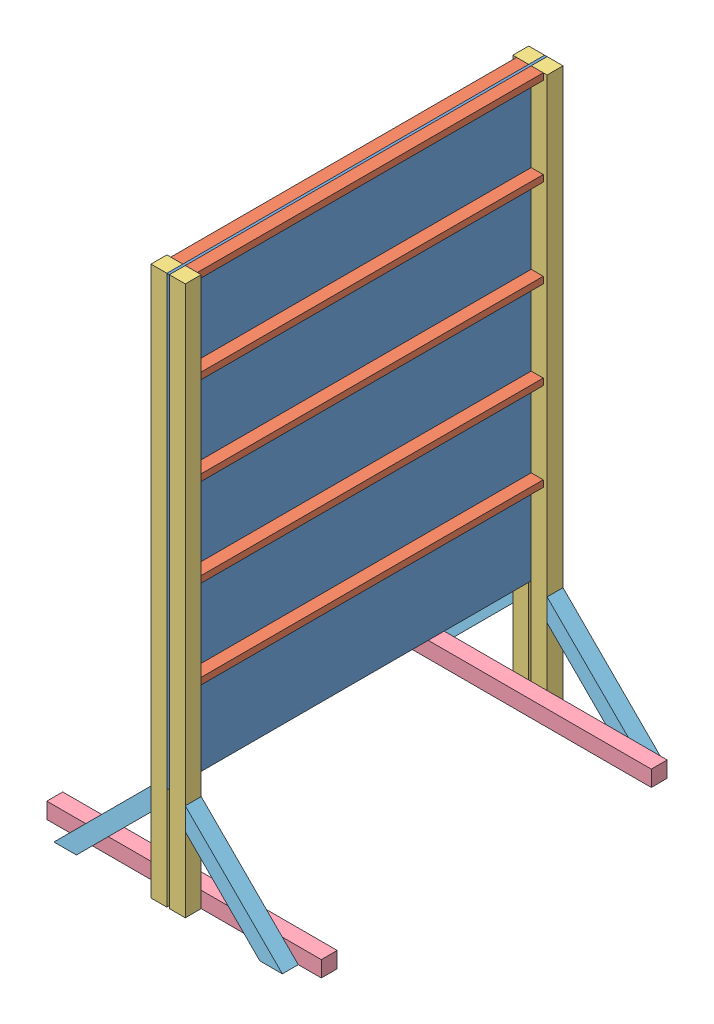
SolidWorks assembly Brett, configuration Standard. Lengths in mm.
Overall size (1000 2041.01 1376).
21 component instances, 5 part files, 60 mates.
Components (placement in the parent):
- Wand-1: Wand [Standard] at (-36.2731 -1608.7946 4318) x (0 0 -1) z (1 0 0) size (1376 1625 9)
- latte1-1: latte1 [Standard] at (-27.2731 -7.7946 3000) size (44 24 1260)
- latte2-1: latte2 [Standard] at (-27.2731 16.2054 2942) x (1 0 0) z (0 -1 0) size (58 58 2000)
- latte2-2: latte2 [Standard] at (-27.2731 16.2054 4260) x (1 0 0) z (0 -1 0) size (58 58 2000)
- latte1-2: latte1 [Standard] at (-27.2731 -649.7946 3000) size (44 24 1260)
- latte1-3: latte1 [Standard] at (-27.2731 -970.7946 3000) size (44 24 1260)
- latte1-4: latte1 [Standard] at (-27.2731 -1291.7946 3000) size (44 24 1260)
- latte1-5: latte1 [Standard] at (-27.2731 -328.7946 3000) size (44 24 1260)
- latte2-3: latte2 [Standard] at (-94.2731 -1983.7946 3000) x (1 0 0) z (0 1 0) size (58 58 2000)
- latte2-4: latte2 [Standard] at (-94.2731 -1983.7946 4318) x (1 0 0) z (0 1 0) size (58 58 2000)
- latte1-6: latte1 [Standard] at (-80.2731 -7.7946 3000) size (44 24 1260)
- latte1-7: latte1 [Standard] at (-80.2731 -328.7946 3000) size (44 24 1260)
- latte1-8: latte1 [Standard] at (-80.2731 -649.7946 3000) size (44 24 1260)
- latte1-9: latte1 [Standard] at (-80.2731 -970.7946 3000) size (44 24 1260)
- latte1-10: latte1 [Standard] at (-80.2731 -1291.7946 3000) size (44 24 1260)
- latte3-1: latte3 [Standard] at (468.2269 -1983.7946 4202) x (0 0 1) z (-1 0 0) size (58 58 1000)
- latte3-2: latte3 [Standard] at (-531.7731 -1983.7946 3058) x (0 0 -1) z (1 0 0) size (58 58 1000)
- latte4-1: latte4 [Standard] at (-10.2853 -1671.2534 3000) x (0 0 -1) z (0.707107 -0.707107 0) size (58 58 500)
- latte4-2: latte4 [Standard] at (-406.8143 -2024.8068 3000) x (0 0 -1) z (0.707107 0.707107 0) size (58 58 500)
- latte4-3: latte4 [Standard] at (343.2681 -2024.8068 4260) x (0 0 1) z (-0.707107 0.707107 0) size (58 58 500)
- latte4-4: latte4 [Standard] at (-53.2609 -1671.2534 4260) x (0 0 1) z (-0.707107 -0.707107 0) size (58 58 500)
Mates (geometry in assembly coordinates):
- Deckungsgleich1: coincident anti-aligned: plane of latte1-1 through (-27.2731 -7.7946 4260) normal (-1 0 0); plane of Wand-1 through (-27.2731 -1608.7946 4318) normal (1 0 0)
- Abstand1: distance = 58 mm aligned: plane of latte1-1 through (-27.2731 -7.7946 3000) normal (0 0 -1); plane of Wand-1 through (-27.2731 -1608.7946 2942) normal (0 0 -1)
- Deckungsgleich3: coincident aligned: plane of latte1-1 through (-27.2731 16.2054 4260) normal (0 1 0); plane of Wand-1 through (-27.2731 16.2054 4318) normal (0 1 0)
- Deckungsgleich4: coincident anti-aligned: plane of Wand-1 through (-27.2731 -1608.7946 4318) normal (1 0 0); plane of latte2-1 through (-27.2731 -1983.7946 2942) normal (-1 0 0)
- Deckungsgleich5: coincident aligned: plane of Wand-1 through (-27.2731 -1608.7946 2942) normal (0 0 -1); plane of latte2-1 through (-27.2731 -1983.7946 2942) normal (0 0 -1)
- Deckungsgleich6: coincident aligned: plane of Wand-1 through (-27.2731 16.2054 4318) normal (0 1 0); plane of latte2-1 through (-27.2731 16.2054 2942) normal (0 1 0)
- Deckungsgleich7: coincident anti-aligned: plane of Wand-1 through (-27.2731 -1608.7946 4318) normal (1 0 0); plane of latte2-2 through (-27.2731 -1983.7946 4260) normal (-1 0 0)
- Deckungsgleich8: coincident aligned: plane of Wand-1 through (-27.2731 -1608.7946 4318) normal (0 0 1); plane of latte2-2 through (-27.2731 -1983.7946 4318) normal (0 0 1)
- Deckungsgleich9: coincident aligned: plane of Wand-1 through (-27.2731 16.2054 4318) normal (0 1 0); plane of latte2-2 through (-27.2731 16.2054 4260) normal (0 1 0)
- Deckungsgleich10: coincident anti-aligned: plane of latte2-1 through (-27.2731 -1983.7946 3000) normal (0 0 1); plane of latte1-2 through (-27.2731 -649.7946 3000) normal (0 0 -1)
- Deckungsgleich11: coincident anti-aligned: plane of latte2-1 through (-27.2731 -1983.7946 3000) normal (0 0 1); plane of latte1-5 through (-27.2731 -328.7946 3000) normal (0 0 -1)
- Deckungsgleich12: coincident anti-aligned: plane of latte2-1 through (-27.2731 -1983.7946 3000) normal (0 0 1); plane of latte1-3 through (-27.2731 -970.7946 3000) normal (0 0 -1)
- Deckungsgleich13: coincident anti-aligned: plane of latte2-1 through (-27.2731 -1983.7946 3000) normal (0 0 1); plane of latte1-4 through (-27.2731 -1291.7946 3000) normal (0 0 -1)
- Deckungsgleich14: coincident anti-aligned: plane of Wand-1 through (-27.2731 -1608.7946 4318) normal (1 0 0); plane of latte1-4 through (-27.2731 -1291.7946 4260) normal (-1 0 0)
- Deckungsgleich15: coincident anti-aligned: plane of Wand-1 through (-27.2731 -1608.7946 4318) normal (1 0 0); plane of latte1-3 through (-27.2731 -970.7946 4260) normal (-1 0 0)
- Deckungsgleich16: coincident anti-aligned: plane of Wand-1 through (-27.2731 -1608.7946 4318) normal (1 0 0); plane of latte1-5 through (-27.2731 -328.7946 4260) normal (-1 0 0)
- Deckungsgleich17: coincident anti-aligned: plane of Wand-1 through (-27.2731 -1608.7946 4318) normal (1 0 0); plane of latte1-2 through (-27.2731 -649.7946 4260) normal (-1 0 0)
- Deckungsgleich18: coincident aligned: line of Wand-1 through (-27.2731 -304.7946 3420) axis (0 0 -1); line of latte1-5 through (-27.2731 -304.7946 4260) axis (0 0 -1)
- Deckungsgleich19: coincident aligned: line of Wand-1 through (-27.2731 -625.7946 3420) axis (0 0 -1); line of latte1-2 through (-27.2731 -625.7946 4260) axis (0 0 -1)
- Deckungsgleich20: coincident aligned: line of Wand-1 through (-27.2731 -946.7946 3420) axis (0 0 -1); line of latte1-3 through (-27.2731 -946.7946 4260) axis (0 0 -1)
- Deckungsgleich21: coincident aligned: line of Wand-1 through (-27.2731 -1267.7946 3420) axis (0 0 -1); line of latte1-4 through (-27.2731 -1267.7946 4260) axis (0 0 -1)
- Deckungsgleich22: coincident anti-aligned: plane of Wand-1 through (-36.2731 -1608.7946 4318) normal (-1 0 0); plane of latte2-3 through (-36.2731 16.2054 3000) normal (1 0 0)
- Deckungsgleich23: coincident aligned: plane of latte2-1 through (-27.2731 -1983.7946 2942) normal (0 0 -1); plane of latte2-3 through (-94.2731 16.2054 2942) normal (0 0 -1)
- Deckungsgleich24: coincident aligned: plane of Wand-1 through (-27.2731 16.2054 4318) normal (0 1 0); plane of latte2-3 through (-94.2731 16.2054 3000) normal (0 1 0)
- Deckungsgleich25: coincident anti-aligned: plane of Wand-1 through (-36.2731 -1608.7946 4318) normal (-1 0 0); plane of latte2-4 through (-36.2731 16.2054 4318) normal (1 0 0)
- Deckungsgleich26: coincident aligned: plane of latte2-2 through (-27.2731 -1983.7946 4318) normal (0 0 1); plane of latte2-4 through (-94.2731 16.2054 4318) normal (0 0 1)
- Deckungsgleich27: coincident aligned: plane of latte2-2 through (-27.2731 16.2054 4260) normal (0 1 0); plane of latte2-4 through (-94.2731 16.2054 4318) normal (0 1 0)
- Deckungsgleich28: coincident anti-aligned: plane of Wand-1 through (-36.2731 -1608.7946 4318) normal (-1 0 0); plane of latte1-10 through (-36.2731 -1291.7946 4260) normal (1 0 0)
- Deckungsgleich30: coincident anti-aligned: plane of Wand-1 through (-36.2731 -1608.7946 4318) normal (-1 0 0); plane of latte1-9 through (-36.2731 -970.7946 4260) normal (1 0 0)
- Deckungsgleich31: coincident anti-aligned: plane of Wand-1 through (-36.2731 -1608.7946 4318) normal (-1 0 0); plane of latte1-8 through (-36.2731 -649.7946 4260) normal (1 0 0)
- Deckungsgleich32: coincident anti-aligned: plane of Wand-1 through (-36.2731 -1608.7946 4318) normal (-1 0 0); plane of latte1-7 through (-36.2731 -328.7946 4260) normal (1 0 0)
- Deckungsgleich33: coincident anti-aligned: plane of Wand-1 through (-36.2731 -1608.7946 4318) normal (-1 0 0); plane of latte1-6 through (-36.2731 -7.7946 4260) normal (1 0 0)
- Deckungsgleich34: coincident aligned: plane of Wand-1 through (-27.2731 16.2054 4318) normal (0 1 0); plane of latte1-6 through (-80.2731 16.2054 4260) normal (0 1 0)
- Deckungsgleich35: coincident anti-aligned: plane of latte2-3 through (-94.2731 16.2054 3000) normal (0 0 1); plane of latte1-6 through (-80.2731 -7.7946 3000) normal (0 0 -1)
- Deckungsgleich36: coincident: line of Wand-1 through (-27.2731 -304.7946 3210) axis (0 0 -1); plane of latte1-7 through (-80.2731 -304.7946 4260) normal (0 1 0)
- Deckungsgleich37: coincident: line of Wand-1 through (-27.2731 -625.7946 3210) axis (0 0 -1); plane of latte1-8 through (-80.2731 -625.7946 4260) normal (0 1 0)
- Deckungsgleich38: coincident: line of Wand-1 through (-27.2731 -946.7946 3210) axis (0 0 -1); plane of latte1-9 through (-80.2731 -946.7946 4260) normal (0 1 0)
- Deckungsgleich39: coincident: line of Wand-1 through (-27.2731 -1267.7946 3210) axis (0 0 -1); plane of latte1-10 through (-80.2731 -1267.7946 4260) normal (0 1 0)
- Deckungsgleich40: coincident anti-aligned: plane of latte2-1 through (-27.2731 -1983.7946 3000) normal (0 0 1); plane of latte1-10 through (-80.2731 -1291.7946 3000) normal (0 0 -1)
- Deckungsgleich42: coincident anti-aligned: plane of latte2-3 through (-94.2731 16.2054 3000) normal (0 0 1); plane of latte1-9 through (-80.2731 -970.7946 3000) normal (0 0 -1)
- Deckungsgleich43: coincident anti-aligned: plane of latte2-3 through (-94.2731 16.2054 3000) normal (0 0 1); plane of latte1-8 through (-80.2731 -649.7946 3000) normal (0 0 -1)
- Deckungsgleich44: coincident anti-aligned: plane of latte2-3 through (-94.2731 16.2054 3000) normal (0 0 1); plane of latte1-7 through (-80.2731 -328.7946 3000) normal (0 0 -1)
- Deckungsgleich45: coincident anti-aligned: plane of latte2-4 through (-94.2731 16.2054 4260) normal (0 0 -1); plane of latte3-1 through (-531.7731 -1983.7946 4260) normal (0 0 1)
- Deckungsgleich46: coincident anti-aligned: plane of latte2-1 through (-27.2731 -1983.7946 3000) normal (0 0 1); plane of latte3-2 through (468.2269 -1983.7946 3000) normal (0 0 -1)
- Abstand2: distance = 504.5 mm aligned: plane of latte3-2 through (468.2269 -1983.7946 3058) normal (1 0 0); plane of latte2-3 through (-36.2731 16.2054 3000) normal (1 0 0)
- Abstand3: distance = 504.5 mm aligned: plane of latte3-1 through (468.2269 -1983.7946 4202) normal (1 0 0); plane of latte2-4 through (-36.2731 16.2054 4318) normal (1 0 0)
- Deckungsgleich49: coincident aligned: plane of latte3-2 through (468.2269 -1983.7946 3058) normal (0 -1 0); plane of latte4-1 through (384.2803 -1983.7946 3000) normal (0 -1 0)
- Deckungsgleich50: coincident anti-aligned: plane of latte3-2 through (468.2269 -1983.7946 3000) normal (0 0 -1); plane of latte4-1 through (343.2681 -2024.8068 3000) normal (0 0 1)
- Deckungsgleich51: coincident anti-aligned: plane of latte2-1 through (30.7269 -1983.7946 2942) normal (1 0 0); plane of latte4-1 through (30.7269 -1712.2656 3000) normal (-1 0 0)
- Deckungsgleich52: coincident aligned: plane of latte3-2 through (468.2269 -1983.7946 3058) normal (0 -1 0); plane of latte4-2 through (-365.8021 -1983.7946 3000) normal (0 -1 0)
- Deckungsgleich53: coincident anti-aligned: plane of latte3-2 through (468.2269 -1983.7946 3000) normal (0 0 -1); plane of latte4-2 through (-53.2609 -1671.2534 3000) normal (0 0 1)
- Deckungsgleich54: coincident anti-aligned: plane of latte2-3 through (-94.2731 16.2054 3000) normal (-1 0 0); plane of latte4-2 through (-94.2731 -1630.2412 3000) normal (1 0 0)
- Deckungsgleich55: coincident aligned: plane of latte3-1 through (-531.7731 -1983.7946 4202) normal (0 -1 0); plane of latte4-3 through (302.2559 -1983.7946 4260) normal (0 -1 0)
- Deckungsgleich56: coincident anti-aligned: plane of latte3-1 through (-531.7731 -1983.7946 4260) normal (0 0 1); plane of latte4-3 through (-10.2853 -1671.2534 4260) normal (0 0 -1)
- Deckungsgleich57: coincident anti-aligned: plane of latte2-2 through (30.7269 -1983.7946 4260) normal (1 0 0); plane of latte4-3 through (30.7269 -1630.2412 4260) normal (-1 0 0)
- Deckungsgleich58: coincident aligned: plane of latte3-1 through (-531.7731 -1983.7946 4202) normal (0 -1 0); plane of latte4-4 through (-447.8265 -1983.7946 4260) normal (0 -1 0)
- Deckungsgleich59: coincident anti-aligned: plane of latte3-1 through (-531.7731 -1983.7946 4260) normal (0 0 1); plane of latte4-4 through (-406.8143 -2024.8068 4260) normal (0 0 -1)
- Deckungsgleich60: coincident anti-aligned: plane of latte2-4 through (-94.2731 16.2054 4318) normal (-1 0 0); plane of latte4-4 through (-94.2731 -1712.2656 4260) normal (1 0 0)
- Deckungsgleich61: coincident aligned: plane of latte2-4 through (-94.2731 -1983.7946 4318) normal (0 -1 0); plane of latte3-1 through (-531.7731 -1983.7946 4202) normal (0 -1 0)
- Deckungsgleich62: coincident aligned: plane of latte2-3 through (-94.2731 -1983.7946 3000) normal (0 -1 0); plane of latte3-2 through (468.2269 -1983.7946 3058) normal (0 -1 0)
